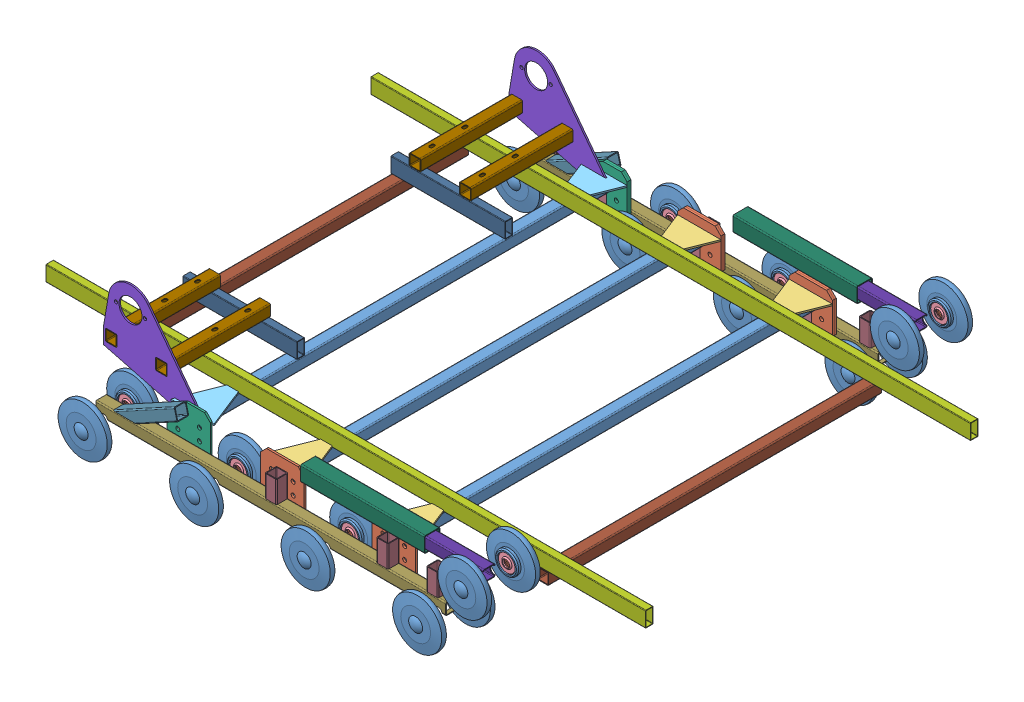
SolidWorks assembly ТП.016.001 - Рама гусеницы, configuration 00. Lengths in mm.
Overall size (1585 378.24 1275.68).
269 component instances, 35 part files, 9 mates.
Components (placement in the parent):
- ТП.016.01.01.01.00 - Рама корпуса-1: ТП.016.01.01.01.00 - Рама корпуса [00] x (-1 0 0) z (0 0 -1) size (1585 284.02 1098)
  - ТП.016.01.01.01.01.00 - Поперечная балка в сборе-1: ТП.016.01.01.01.01.00 - Поперечная балка в сборе [Центральная] at (824.8534 -30 544) size (112 110.77 1078)
    - ТП.016.01.01.01.01.01 - Поперечная балка (30х30)-1: ТП.016.01.01.01.01.01 - Поперечная балка (30х30) [--] at origin size (30 30 1068)
    - ТП.016.01.01.01.01.02 - Пластина кронштейна (5мм)-1: ТП.016.01.01.01.01.02 - Пластина кронштейна (5мм) [--] at (0 -56.7738 -5) size (112 110.77 5)
    - ТП.016.01.01.01.01.03 - Косынка верхняя (4мм)-1: ТП.016.01.01.01.01.03 - Косынка верхняя (4мм) [--] at (0 30 -10) size (112 4 104)
    - ТП.016.01.01.01.01.02 - Пластина кронштейна (5мм)-2: ТП.016.01.01.01.01.02 - Пластина кронштейна (5мм) [--] at (0 -56.7738 -1083) x (-1 0 0) z (0 0 -1) size (112 110.77 5)
    - ТП.016.01.01.01.01.03 - Косынка верхняя (4мм)-2: ТП.016.01.01.01.01.03 - Косынка верхняя (4мм) [--] at (0 30 -1078) x (-1 0 0) z (0 0 -1) size (112 4 104)
    - ТП.016.01.01.01.01.04 - Косынка нижняя (4мм)-2: ТП.016.01.01.01.01.04 - Косынка нижняя (4мм) [--] at (0 0 -1078) x (-1 0 0) z (0 0 -1) size (4 53.77 53.77)
    - ТП.016.01.01.01.01.04 - Косынка нижняя (4мм)-3: ТП.016.01.01.01.01.04 - Косынка нижняя (4мм) [--] at (0 0 -10) size (4 53.77 53.77)
    - ТП.016.01.01.01.01.05 - Пластина кронштейна задняя (5мм)-1: ТП.016.01.01.01.01.05 - Пластина кронштейна задняя (5мм) [--] at (0 -56.7738 -1083) x (-1 0 0) z (0 0 -1) size (112 110.77 5) (hidden)
    - ТП.016.01.01.01.01.06 - Косынка верхняя задняя (4мм)-1: ТП.016.01.01.01.01.06 - Косынка верхняя задняя (4мм) [--] at (-15 30 -1078) x (-1 0 0) z (0 0 -1) size (111.99 4 104) (hidden)
    - ТП.016.01.01.01.01.05 - Пластина кронштейна задняя (5мм)-2: ТП.016.01.01.01.01.05 - Пластина кронштейна задняя (5мм) [--] at (0 -56.7738 -10) x (-1 0 0) z (0 0 -1) size (112 110.77 5) (hidden)
    - ТП.016.01.01.01.01.06 - Косынка верхняя задняя (4мм)-2: ТП.016.01.01.01.01.06 - Косынка верхняя задняя (4мм) [--] at (-15 34 -10) x (-1 0 0) z (0 0 1) size (111.99 4 104) (hidden)
  - ТП.016.01.01.01.01.00 - Поперечная балка в сборе-2: ТП.016.01.01.01.01.00 - Поперечная балка в сборе [Центральная] at (536.5267 -30 544) size (112 110.77 1078)
    - ТП.016.01.01.01.01.01 - Поперечная балка (30х30)-1: ТП.016.01.01.01.01.01 - Поперечная балка (30х30) [--] at origin size (30 30 1068)
    - ТП.016.01.01.01.01.02 - Пластина кронштейна (5мм)-1: ТП.016.01.01.01.01.02 - Пластина кронштейна (5мм) [--] at (0 -56.7738 -5) size (112 110.77 5)
    - ТП.016.01.01.01.01.03 - Косынка верхняя (4мм)-1: ТП.016.01.01.01.01.03 - Косынка верхняя (4мм) [--] at (0 30 -10) size (112 4 104)
    - ТП.016.01.01.01.01.02 - Пластина кронштейна (5мм)-2: ТП.016.01.01.01.01.02 - Пластина кронштейна (5мм) [--] at (0 -56.7738 -1083) x (-1 0 0) z (0 0 -1) size (112 110.77 5)
    - ТП.016.01.01.01.01.03 - Косынка верхняя (4мм)-2: ТП.016.01.01.01.01.03 - Косынка верхняя (4мм) [--] at (0 30 -1078) x (-1 0 0) z (0 0 -1) size (112 4 104)
    - ТП.016.01.01.01.01.04 - Косынка нижняя (4мм)-2: ТП.016.01.01.01.01.04 - Косынка нижняя (4мм) [--] at (0 0 -1078) x (-1 0 0) z (0 0 -1) size (4 53.77 53.77)
    - ТП.016.01.01.01.01.04 - Косынка нижняя (4мм)-3: ТП.016.01.01.01.01.04 - Косынка нижняя (4мм) [--] at (0 0 -10) size (4 53.77 53.77)
    - ТП.016.01.01.01.01.05 - Пластина кронштейна задняя (5мм)-1: ТП.016.01.01.01.01.05 - Пластина кронштейна задняя (5мм) [--] at (0 -56.7738 -1083) x (-1 0 0) z (0 0 -1) size (112 110.77 5) (hidden)
    - ТП.016.01.01.01.01.06 - Косынка верхняя задняя (4мм)-1: ТП.016.01.01.01.01.06 - Косынка верхняя задняя (4мм) [--] at (-15 30 -1078) x (-1 0 0) z (0 0 -1) size (111.99 4 104) (hidden)
    - ТП.016.01.01.01.01.05 - Пластина кронштейна задняя (5мм)-2: ТП.016.01.01.01.01.05 - Пластина кронштейна задняя (5мм) [--] at (0 -56.7738 -10) x (-1 0 0) z (0 0 -1) size (112 110.77 5) (hidden)
    - ТП.016.01.01.01.01.06 - Косынка верхняя задняя (4мм)-2: ТП.016.01.01.01.01.06 - Косынка верхняя задняя (4мм) [--] at (-15 34 -10) x (-1 0 0) z (0 0 1) size (111.99 4 104) (hidden)
  - ТП.016.01.01.01.01.00 - Поперечная балка в сборе-3: ТП.016.01.01.01.01.00 - Поперечная балка в сборе [Задняя] at (1067.2668 -30 544) size (112 110.77 1078)
    - ТП.016.01.01.01.01.01 - Поперечная балка (30х30)-1: ТП.016.01.01.01.01.01 - Поперечная балка (30х30) [Под лебедку] at origin size (30 30 1068)
    - ТП.016.01.01.01.01.02 - Пластина кронштейна (5мм)-1: ТП.016.01.01.01.01.02 - Пластина кронштейна (5мм) [--] at (0 -56.7738 -5) size (112 110.77 5) (hidden)
    - ТП.016.01.01.01.01.03 - Косынка верхняя (4мм)-1: ТП.016.01.01.01.01.03 - Косынка верхняя (4мм) [--] at (0 30 -10) size (112 4 104) (hidden)
    - ТП.016.01.01.01.01.02 - Пластина кронштейна (5мм)-2: ТП.016.01.01.01.01.02 - Пластина кронштейна (5мм) [--] at (0 -56.7738 -1083) x (-1 0 0) z (0 0 -1) size (112 110.77 5) (hidden)
    - ТП.016.01.01.01.01.03 - Косынка верхняя (4мм)-2: ТП.016.01.01.01.01.03 - Косынка верхняя (4мм) [--] at (0 30 -1078) x (-1 0 0) z (0 0 -1) size (112 4 104) (hidden)
    - ТП.016.01.01.01.01.04 - Косынка нижняя (4мм)-2: ТП.016.01.01.01.01.04 - Косынка нижняя (4мм) [--] at (0 0 -1078) x (-1 0 0) z (0 0 -1) size (4 53.77 53.77)
    - ТП.016.01.01.01.01.04 - Косынка нижняя (4мм)-3: ТП.016.01.01.01.01.04 - Косынка нижняя (4мм) [--] at (0 0 -10) size (4 53.77 53.77)
    - ТП.016.01.01.01.01.05 - Пластина кронштейна задняя (5мм)-1: ТП.016.01.01.01.01.05 - Пластина кронштейна задняя (5мм) [--] at (0 -56.7738 -1083) x (-1 0 0) z (0 0 -1) size (112 110.77 5)
    - ТП.016.01.01.01.01.06 - Косынка верхняя задняя (4мм)-1: ТП.016.01.01.01.01.06 - Косынка верхняя задняя (4мм) [--] at (-15 30 -1078) x (-1 0 0) z (0 0 -1) size (111.99 4 104)
    - ТП.016.01.01.01.01.05 - Пластина кронштейна задняя (5мм)-2: ТП.016.01.01.01.01.05 - Пластина кронштейна задняя (5мм) [--] at (0 -56.7738 -10) x (-1 0 0) z (0 0 -1) size (112 110.77 5)
    - ТП.016.01.01.01.01.06 - Косынка верхняя задняя (4мм)-2: ТП.016.01.01.01.01.06 - Косынка верхняя задняя (4мм) [--] at (-15 34 -10) x (-1 0 0) z (0 0 1) size (111.99 4 104)
  - ТП.016.01.01.01.02 - Балка платформы боковая (40х20)-1: ТП.016.01.01.01.02 - Балка платформы боковая (40х20) [--] at (250 0 -420) x (0 0 -1) z (1 0 0) size (20 40 1550)
  - ТП.016.01.01.01.02 - Балка платформы боковая (40х20)-2: ТП.016.01.01.01.02 - Балка платформы боковая (40х20) [--] at (250 0 420) x (0 0 -1) z (1 0 0) size (20 40 1550)
  - Схема рамы ЭСКИЗ-1: Схема рамы ЭСКИЗ [--] x (0 0 -1) z (1 0 0) size (559 0 1052.27)
  - ТП.016.01.01.01.03.00 - Опора редуктора-1: ТП.016.01.01.01.03.00 - Опора редуктора [Правая] at (1235 143.2262 -526.5) x (-1 0 0) z (0 0 -1) size (276.73 227.25 267.34)
    - ТП.016.01.01.01.03.01 - Щека ведущей оси (4мм)-1: ТП.016.01.01.01.03.01 - Щека ведущей оси (4мм) [--] at origin size (249.73 227.25 4)
    - ТП.016.01.01.01.03.02 - Балка опоры ребуктора (30х30)-1: ТП.016.01.01.01.03.02 - Балка опоры ребуктора (30х30) [--] at (65 -72 0) size (30 30 267.34)
    - ТП.016.01.01.01.03.02 - Балка опоры ребуктора (30х30)-2: ТП.016.01.01.01.03.02 - Балка опоры ребуктора (30х30) [--] at (-65 -72 0) size (30 30 267.34)
    - ТП.016.01.01.01.03.02 - Балка опоры ребуктора (30х30)-3: ТП.016.01.01.01.03.02 - Балка опоры ребуктора (30х30) [--] at (95 -72 -4) x (-1 0 0) z (0 0 -1) size (30 30 267.34) (hidden)
    - ТП.016.01.01.01.03.02 - Балка опоры ребуктора (30х30)-4: ТП.016.01.01.01.03.02 - Балка опоры ребуктора (30х30) [--] at (-35 -72 -4) x (-1 0 0) z (0 0 -1) size (30 30 267.34) (hidden)
    - ТП.016.01.01.01.03.03 - Пол под редуктор (3мм)-1: ТП.016.01.01.01.03.03 - Пол под редуктор (3мм) [--] at (65 -143.2262 -181.9182) x (0 0 -1) z (1 0 0) size (130.84 76.23 264.73)
  - ТП.016.01.01.01.03.00 - Опора редуктора-2: ТП.016.01.01.01.03.00 - Опора редуктора [Левая] at (1235 143.2262 522.5) x (-1 0 0) z (0 0 -1) size (276.73 227.25 267.34)
    - ТП.016.01.01.01.03.01 - Щека ведущей оси (4мм)-1: ТП.016.01.01.01.03.01 - Щека ведущей оси (4мм) [--] at origin size (249.73 227.25 4)
    - ТП.016.01.01.01.03.02 - Балка опоры ребуктора (30х30)-1: ТП.016.01.01.01.03.02 - Балка опоры ребуктора (30х30) [--] at (65 -72 0) size (30 30 267.34) (hidden)
    - ТП.016.01.01.01.03.02 - Балка опоры ребуктора (30х30)-2: ТП.016.01.01.01.03.02 - Балка опоры ребуктора (30х30) [--] at (-65 -72 0) size (30 30 267.34) (hidden)
    - ТП.016.01.01.01.03.02 - Балка опоры ребуктора (30х30)-3: ТП.016.01.01.01.03.02 - Балка опоры ребуктора (30х30) [--] at (95 -72 -4) x (-1 0 0) z (0 0 -1) size (30 30 267.34)
    - ТП.016.01.01.01.03.02 - Балка опоры ребуктора (30х30)-4: ТП.016.01.01.01.03.02 - Балка опоры ребуктора (30х30) [--] at (-35 -72 -4) x (-1 0 0) z (0 0 -1) size (30 30 267.34)
    - ТП.016.01.01.01.03.03 - Пол под редуктор (3мм)-1: ТП.016.01.01.01.03.03 - Пол под редуктор (3мм) [--] at (65 -143.2262 177.9182) x (0 0 -1) z (1 0 0) size (130.84 76.23 264.73)
  - ТП.016.01.01.01.04 - Опора короткая под редуктор (40х20)-1: ТП.016.01.01.01.04 - Опора короткая под редуктор (40х20) [--] at (1052.2668 0 -259.1637) x (0 0 -1) z (1 0 0) size (20 40 294.73)
  - ТП.016.01.01.01.04 - Опора короткая под редуктор (40х20)-2: ТП.016.01.01.01.04 - Опора короткая под редуктор (40х20) [--] at (1052.2668 0 279.1637) x (0 0 -1) z (1 0 0) size (20 40 294.73)
  - ТП.016.01.01.01.05 - Поперечина короткая (30х30)-1: ТП.016.01.01.01.05 - Поперечина короткая (30х30) [--] at (1347 0 0) size (30 30 860)
  - ТП.016.01.01.01.05 - Поперечина короткая (30х30)-2: ТП.016.01.01.01.05 - Поперечина короткая (30х30) [--] at (280 0 0) size (30 30 860)
  - ТП.016.01.01.01.06 - Поддержка центральная (40х20)-1: ТП.016.01.01.01.06 - Поддержка центральная (40х20) [--] at (45 -9.1741 -23) x (0 0 1) z (-1 0 0) size (20 40 596.53)
  - ТП.016.01.01.01.06 - Поддержка центральная (40х20)-2: ТП.016.01.01.01.06 - Поддержка центральная (40х20) [--] at (45 -9.1741 43) x (0 0 1) z (-1 0 0) size (20 40 596.53)
  - ТП.016.01.01.01.07 - Пол перед (3мм)-1: ТП.016.01.01.01.07 - Пол перед (3мм) [Правый] at (0 0 -410) x (0 0 -1) z (1 0 0) size (377 29.49 517.11)
  - ТП.016.01.01.01.07 - Пол перед (3мм)-2: ТП.016.01.01.01.07 - Пол перед (3мм) [Левый] at (0 0 -344) x (0 0 -1) z (1 0 0) size (754 29.49 517.11)
  - ТП.016.01.01.01.08 - Пол центр (2мм)-1: ТП.016.01.01.01.08 - Пол центр (2мм) [--] at (250 0 0) x (0 0 -1) z (1 0 0) size (820 12 817.27)
  - ТП.016.01.01.01.09 - Задний бампер (40х20)-1: ТП.016.01.01.01.09 - Задний бампер (40х20) [--] at (1570 0 0) size (20 40 860)
  - ТП.016.01.01.01.10 - Пол капота (3мм)-1: ТП.016.01.01.01.10 - Пол капота (3мм) [--] at (1550 0 0) x (0 0 1) z (-1 0 0) size (820 13 482.73)
  - Гайка (ГОСТ ISO 4032-2014)-1: Гайка (ГОСТ ISO 4032-2014) [Гайка М6 (ГОСТ ISO 4032)] at (153.1386 -2.6 64.0253) x (-0.998033 0 -0.062689) z (0 1 0) size (10 11.05 5.2)
  - Гайка (ГОСТ ISO 4032-2014)-2: Гайка (ГОСТ ISO 4032-2014) [Гайка М6 (ГОСТ ISO 4032)] at (403.0634 -2.6 70.156) x (-0.991964 0 0.126519) z (0 1 0) size (10 11.05 5.2)
  - Гайка (ГОСТ ISO 4032-2014)-3: Гайка (ГОСТ ISO 4032-2014) [Гайка М6 (ГОСТ ISO 4032)] at (672.9822 -2.6 76.7772) x (-0.941367 0 0.337385) z (0 1 0) size (10 11.05 5.2)
  - Гайка (ГОСТ ISO 4032-2014)-4: Гайка (ГОСТ ISO 4032-2014) [Гайка М6 (ГОСТ ISO 4032)] at (1021.6211 -2.6 85.3294) x (-0.83604 0 0.548669) z (0 1 0) size (10 11.05 5.2)
  - Гайка (ГОСТ ISO 4032-2014)-5: Гайка (ГОСТ ISO 4032-2014) [Гайка М6 (ГОСТ ISO 4032)] at (1021.6211 -2.6 -85.3294) x (-0.680834 0 0.732437) z (0 1 0) size (10 11.05 5.2)
  - Гайка (ГОСТ ISO 4032-2014)-6: Гайка (ГОСТ ISO 4032-2014) [Гайка М6 (ГОСТ ISO 4032)] at (672.9822 -2.6 -76.7772) x (-0.498939 0 0.866637) z (0 1 0) size (10 11.05 5.2)
  - Гайка (ГОСТ ISO 4032-2014)-7: Гайка (ГОСТ ISO 4032-2014) [Гайка М6 (ГОСТ ISO 4032)] at (403.0634 -2.6 -70.156) x (-0.323185 0 0.946336) z (0 1 0) size (10 11.05 5.2)
  - Гайка (ГОСТ ISO 4032-2014)-8: Гайка (ГОСТ ISO 4032-2014) [Гайка М6 (ГОСТ ISO 4032)] at (153.1386 -2.6 -64.0253) x (-0.182176 0 0.983266) z (0 1 0) size (10 11.05 5.2)
- ТП.016.02.00 - Гусеничный модуль в сборе-1: ТП.016.02.00 - Гусеничный модуль в сборе [Левый] at (-392.3634 -86.7738 -559) x (-1 0 0) z (0 0 -1) size (1147.02 302.71 157.68)
  - ТП.016.02.01.00 - Модуль гусеницы силовой-1: ТП.016.02.01.00 - Модуль гусеницы силовой [Левый] at origin size (904.98 176.07 133.68)
    - ТП.016.02.01.01.00 - Рама гусеницы с осями-1: ТП.016.02.01.01.00 - Рама гусеницы с осями [00] at origin size (904.98 176.07 133.68)
      - ТП.016.02.01.01.01 - Нижняя балка гуленицы (30х30)-1: ТП.016.02.01.01.01 - Нижняя балка гуленицы (30х30) [--] at origin size (904.98 30 30)
      - ТП.016.02.01.01.02(02) - Ось цельная 21_3мм-1: ТП.016.02.01.01.02(02) - Ось цельная 21_3мм [--] x (0 0 1) z (-1 0 0) size (133.68 21.3 21.3)
      - ТП.016.02.01.01.02(02) - Ось цельная 21_3мм-2: ТП.016.02.01.01.02(02) - Ось цельная 21_3мм [--] at (288.3267 0 0) x (0 0 1) z (-0.987351 0.158553 0) size (133.68 21.3 21.3)
      - ТП.016.02.01.01.02(02) - Ось цельная 21_3мм-3: ТП.016.02.01.01.02(02) - Ось цельная 21_3мм [--] at (576.6534 0 0) x (0 0 1) z (-0.959125 0.282984 0) size (133.68 21.3 21.3)
      - ТП.016.02.01.01.02(02) - Ось цельная 21_3мм-4: ТП.016.02.01.01.02(02) - Ось цельная 21_3мм [--] at (864.9801 0 0) x (0 0 1) z (-0.928571 0.371154 0) size (133.68 21.3 21.3)
      - ТП.016.02.01.01.03 - Связка балок гусеничного модуля-1: ТП.016.02.01.01.03 - Связка балок гусеничного модуля [--] at (0 86.7738 0) x (-1 0 0) z (0 0 -1) size (30 56.77 30)
      - ТП.016.02.01.01.03 - Связка балок гусеничного модуля-2: ТП.016.02.01.01.03 - Связка балок гусеничного модуля [--] at (129.1634 86.7738 0) x (-1 0 0) z (0 0 -1) size (30 56.77 30)
      - ТП.016.02.01.01.03 - Связка балок гусеничного модуля-3: ТП.016.02.01.01.03 - Связка балок гусеничного модуля [--] at (417.4901 86.7738 0) x (-1 0 0) z (0 0 -1) size (30 56.77 30)
      - ТП.016.02.01.01.04 - Верхняя балка рамы гусеницы-1: ТП.016.02.01.01.04 - Верхняя балка рамы гусеницы [--] at (0 136.7738 0) x (0 0 1) z (-1 0 0) size (30 129.94 872.16)
      - ТП.016.02.01.01.05 - Задняя косая-1: ТП.016.02.01.01.05 - Задняя косая [--] at (864.9801 0 -15) x (0 0 -1) z (0.877984 -0.478691 0) size (30 30 181.27)
      - ТП.016.02.01.01.06.00 - Стакан натяжителя-1: ТП.016.02.01.01.06.00 - Стакан натяжителя [00] at (30 136.7738 0) x (-1 0 0) z (0 0 -1) size (320 50.91 50.91)
        - ТП.016.02.01.01.06.01 - Рубашка штока ролика натяжного-1: ТП.016.02.01.01.06.01 - Рубашка штока ролика натяжного [--] at origin size (320 40 40)
        - ТП.016.02.01.01.06.02 - Гайка рубашки штока-1: ТП.016.02.01.01.06.02 - Гайка рубашки штока [--] at (-320 0 0) x (0 -0.713098 -0.701064) z (1 0 0) size (36 36 20)
    - ТП.016.01.01.01.01.02 - Пластина кронштейна (5мм)-1: ТП.016.01.01.01.01.02 - Пластина кронштейна (5мм) [--] at (144.1634 0 20) size (112 110.77 5) (hidden)
    - ТП.016.01.01.01.01.02 - Пластина кронштейна (5мм)-2: ТП.016.01.01.01.01.02 - Пластина кронштейна (5мм) [--] at (432.4901 0 20) size (112 110.77 5) (hidden)
    - ТП.016.01.01.01.01.05 - Пластина кронштейна задняя (5мм)-1: ТП.016.01.01.01.01.05 - Пластина кронштейна задняя (5мм) [--] at (674.9034 0 15) x (-1 0 0) z (0 0 -1) size (112 110.77 5) (hidden)
    - ТП.016.01.01.01.01.02 - Пластина кронштейна (5мм)-4: ТП.016.01.01.01.01.02 - Пластина кронштейна (5мм) [--] at (144.1634 0 -20) x (-1 0 0) z (0 0 -1) size (112 110.77 5)
    - ТП.016.01.01.01.01.02 - Пластина кронштейна (5мм)-6: ТП.016.01.01.01.01.02 - Пластина кронштейна (5мм) [--] at (432.4901 0 -20) x (-1 0 0) z (0 0 -1) size (112 110.77 5)
    - ТП.016.01.01.01.01.05 - Пластина кронштейна задняя (5мм)-2: ТП.016.01.01.01.01.05 - Пластина кронштейна задняя (5мм) [--] at (674.9034 0 -20) x (-1 0 0) z (0 0 -1) size (112 110.77 5)
  - ТП.016.02.02.00 - Натяжитель гусеницы-1: ТП.016.02.02.00 - Натяжитель гусеницы [00] at (-117 136.7738 0) x (-1 0 0) z (0 0 1) size (371.74 149.44 157.68)
    - ТП.016.02.02.01.00 - Толкатель натяжки-1: ТП.016.02.02.01.00 - Толкатель натяжки [00] at origin size (311.12 30 133.68)
      - ТП.016.02.02.01.01 - Шток натяжного ролика (30х30)-1: ТП.016.02.02.01.01 - Шток натяжного ролика (30х30) [--] at origin size (297.02 30 30)
      - ТП.016.02.01.01.02(02) - Ось цельная 21_3мм-1: ТП.016.02.01.01.02(02) - Ось цельная 21_3мм [--] x (0 0 1) z (-0.910058 0.41448 0) size (133.68 21.3 21.3)
      - ТП.016.02.02.01.02 - Заглушка штока-1: ТП.016.02.02.01.02 - Заглушка штока [--] at (-297.0168 0 0) x (0 -1 0) z (1 0 0) size (26 26 20)
    - Каток 129(47) в сборе-1: Каток 129(47) в сборе [00] at (0 0 62.8416) x (0 0 1) z (1 0 0) size (35.7 129 129)
      - Каток 129(47)-1: Каток 129(47) [--] at origin size (35 129 129)
      - Подшипник ГОСТ 8338-75 -1: Подшипник ГОСТ 8338-75  [Подшипник 204 ГОСТ 8338-75] at (-1 0 0) x (1 0 0) z (0 -0.327433 -0.944874) size (14 47 47)
      - Стопор внутренний до 165мм (ГОСТ 13943-86)-1: Стопор внутренний до 165мм (ГОСТ 13943-86) [Кольцо 47] at (-8 0 0) x (0 0.910839 0.412761) z (-1 0 0) size (49.5 51.2 1.7)
      - Сальник 47х20-1: Сальник 47х20 [--] at (-9.7 0 0) x (-1 0 0) z (0 0.937697 -0.347453) size (10 47 47)
    - Каток 129(47) в сборе-2: Каток 129(47) в сборе [00] at (0 0 -62.8416) x (0 0 -1) z (-0.173648 0.984808 0) size (35.7 129 129)
      - Каток 129(47)-1: Каток 129(47) [--] at origin size (35 129 129)
      - Подшипник ГОСТ 8338-75 -1: Подшипник ГОСТ 8338-75  [Подшипник 204 ГОСТ 8338-75] at (-1 0 0) x (1 0 0) z (0 -0.327433 -0.944874) size (14 47 47)
      - Стопор внутренний до 165мм (ГОСТ 13943-86)-1: Стопор внутренний до 165мм (ГОСТ 13943-86) [Кольцо 47] at (-8 0 0) x (0 0.910839 0.412761) z (-1 0 0) size (49.5 51.2 1.7)
      - Сальник 47х20-1: Сальник 47х20 [--] at (-9.7 0 0) x (-1 0 0) z (0 0.937697 -0.347453) size (10 47 47)
    - ТП.016.02.02.02 - Шайба оси-1: ТП.016.02.02.02 - Шайба оси [--] at (0 0 -66.3614) x (0 0 1) z (0.48394 0.875101 0) size (4 24 24)
    - Болты с шестигранной головкой кт.В (ГОСТ 7798-70)-1: Болты с шестигранной головкой кт.В (ГОСТ 7798-70) [Болт М6-6gx14(S10) ГОСТ 7798-77] at (0 0 -69.3416) x (0 0 1) z (0.143998 -0.989578 0) size (18 10.9 10)
    - ТП.016.02.02.02 - Шайба оси-2: ТП.016.02.02.02 - Шайба оси [--] at (0 0 66.3614) x (0 0 -1) z (0.777771 0.628548 0) size (4 24 24)
    - Болты с шестигранной головкой кт.В (ГОСТ 7798-70)-2: Болты с шестигранной головкой кт.В (ГОСТ 7798-70) [Болт М6-6gx14(S10) ГОСТ 7798-77] at (0 0 69.3416) x (0 0 -1) z (-0.999549 -0.030028 0) size (18 10.9 10)
  - ТП.016.02.03 - Винт натяжителя-1: ТП.016.02.03 - Винт натяжителя [--] at (350.0168 136.7738 0) x (0 -0.01927 -0.999814) z (-1 0 0) size (20 20 231.35)
  - Каток 129(47) в сборе-1: Каток 129(47) в сборе [00] at (0 0 -62.8416) x (0 0 -1) z (-0.261474 0.96521 0) size (35.7 129 129)
    - Каток 129(47)-1: Каток 129(47) [--] at origin size (35 129 129)
    - Подшипник ГОСТ 8338-75 -1: Подшипник ГОСТ 8338-75  [Подшипник 204 ГОСТ 8338-75] at (-1 0 0) x (1 0 0) z (0 -0.327433 -0.944874) size (14 47 47)
    - Стопор внутренний до 165мм (ГОСТ 13943-86)-1: Стопор внутренний до 165мм (ГОСТ 13943-86) [Кольцо 47] at (-8 0 0) x (0 0.910839 0.412761) z (-1 0 0) size (49.5 51.2 1.7)
    - Сальник 47х20-1: Сальник 47х20 [--] at (-9.7 0 0) x (-1 0 0) z (0 0.937697 -0.347453) size (10 47 47)
  - Каток 129(47) в сборе-2: Каток 129(47) в сборе [00] at (288.3267 0 -62.8416) x (0 0 -1) z (-0.411203 0.911544 0) size (35.7 129 129)
    - Каток 129(47)-1: Каток 129(47) [--] at origin size (35 129 129)
    - Подшипник ГОСТ 8338-75 -1: Подшипник ГОСТ 8338-75  [Подшипник 204 ГОСТ 8338-75] at (-1 0 0) x (1 0 0) z (0 -0.327433 -0.944874) size (14 47 47)
    - Стопор внутренний до 165мм (ГОСТ 13943-86)-1: Стопор внутренний до 165мм (ГОСТ 13943-86) [Кольцо 47] at (-8 0 0) x (0 0.910839 0.412761) z (-1 0 0) size (49.5 51.2 1.7)
    - Сальник 47х20-1: Сальник 47х20 [--] at (-9.7 0 0) x (-1 0 0) z (0 0.937697 -0.347453) size (10 47 47)
  - Каток 129(47) в сборе-4: Каток 129(47) в сборе [00] at (576.6534 0 -62.8416) x (0 0 -1) z (-0.523925 0.851764 0) size (35.7 129 129)
    - Каток 129(47)-1: Каток 129(47) [--] at origin size (35 129 129)
    - Подшипник ГОСТ 8338-75 -1: Подшипник ГОСТ 8338-75  [Подшипник 204 ГОСТ 8338-75] at (-1 0 0) x (1 0 0) z (0 -0.327433 -0.944874) size (14 47 47)
    - Стопор внутренний до 165мм (ГОСТ 13943-86)-1: Стопор внутренний до 165мм (ГОСТ 13943-86) [Кольцо 47] at (-8 0 0) x (0 0.910839 0.412761) z (-1 0 0) size (49.5 51.2 1.7)
    - Сальник 47х20-1: Сальник 47х20 [--] at (-9.7 0 0) x (-1 0 0) z (0 0.937697 -0.347453) size (10 47 47)
  - Каток 129(47) в сборе-6: Каток 129(47) в сборе [00] at (864.9801 0 -62.8416) x (0 0 -1) z (0.601039 -0.79922 0) size (35.7 129 129)
    - Каток 129(47)-1: Каток 129(47) [--] at origin size (35 129 129)
    - Подшипник ГОСТ 8338-75 -1: Подшипник ГОСТ 8338-75  [Подшипник 204 ГОСТ 8338-75] at (-1 0 0) x (1 0 0) z (0 -0.327433 -0.944874) size (14 47 47)
    - Стопор внутренний до 165мм (ГОСТ 13943-86)-1: Стопор внутренний до 165мм (ГОСТ 13943-86) [Кольцо 47] at (-8 0 0) x (0 0.910839 0.412761) z (-1 0 0) size (49.5 51.2 1.7)
    - Сальник 47х20-1: Сальник 47х20 [--] at (-9.7 0 0) x (-1 0 0) z (0 0.937697 -0.347453) size (10 47 47)
  - Каток 129(47) в сборе-8: Каток 129(47) в сборе [00] at (864.9801 0 62.8416) x (0 0 1) z (0.907466 0.420125 0) size (35.7 129 129)
    - Каток 129(47)-1: Каток 129(47) [--] at origin size (35 129 129)
    - Подшипник ГОСТ 8338-75 -1: Подшипник ГОСТ 8338-75  [Подшипник 204 ГОСТ 8338-75] at (-1 0 0) x (1 0 0) z (0 -0.327433 -0.944874) size (14 47 47)
    - Стопор внутренний до 165мм (ГОСТ 13943-86)-1: Стопор внутренний до 165мм (ГОСТ 13943-86) [Кольцо 47] at (-8 0 0) x (0 0.910839 0.412761) z (-1 0 0) size (49.5 51.2 1.7)
    - Сальник 47х20-1: Сальник 47х20 [--] at (-9.7 0 0) x (-1 0 0) z (0 0.937697 -0.347453) size (10 47 47)
  - Каток 129(47) в сборе-10: Каток 129(47) в сборе [00] at (576.6534 0 62.8416) x (0 0 1) z (0.820726 0.571322 0) size (35.7 129 129)
    - Каток 129(47)-1: Каток 129(47) [--] at origin size (35 129 129)
    - Подшипник ГОСТ 8338-75 -1: Подшипник ГОСТ 8338-75  [Подшипник 204 ГОСТ 8338-75] at (-1 0 0) x (1 0 0) z (0 -0.327433 -0.944874) size (14 47 47)
    - Стопор внутренний до 165мм (ГОСТ 13943-86)-1: Стопор внутренний до 165мм (ГОСТ 13943-86) [Кольцо 47] at (-8 0 0) x (0 0.910839 0.412761) z (-1 0 0) size (49.5 51.2 1.7)
    - Сальник 47х20-1: Сальник 47х20 [--] at (-9.7 0 0) x (-1 0 0) z (0 0.937697 -0.347453) size (10 47 47)
  - Каток 129(47) в сборе-12: Каток 129(47) в сборе [00] at (288.3267 0 62.8416) x (0 0 1) z (0.709048 0.70516 0) size (35.7 129 129)
    - Каток 129(47)-1: Каток 129(47) [--] at origin size (35 129 129)
    - Подшипник ГОСТ 8338-75 -1: Подшипник ГОСТ 8338-75  [Подшипник 204 ГОСТ 8338-75] at (-1 0 0) x (1 0 0) z (0 -0.327433 -0.944874) size (14 47 47)
    - Стопор внутренний до 165мм (ГОСТ 13943-86)-1: Стопор внутренний до 165мм (ГОСТ 13943-86) [Кольцо 47] at (-8 0 0) x (0 0.910839 0.412761) z (-1 0 0) size (49.5 51.2 1.7)
    - Сальник 47х20-1: Сальник 47х20 [--] at (-9.7 0 0) x (-1 0 0) z (0 0.937697 -0.347453) size (10 47 47)
  - Каток 129(47) в сборе-14: Каток 129(47) в сборе [00] at (0 0 62.8416) x (0 0 1) z (0.575827 0.817572 0) size (35.7 129 129)
    - Каток 129(47)-1: Каток 129(47) [--] at origin size (35 129 129)
    - Подшипник ГОСТ 8338-75 -1: Подшипник ГОСТ 8338-75  [Подшипник 204 ГОСТ 8338-75] at (-1 0 0) x (1 0 0) z (0 -0.327433 -0.944874) size (14 47 47)
    - Стопор внутренний до 165мм (ГОСТ 13943-86)-1: Стопор внутренний до 165мм (ГОСТ 13943-86) [Кольцо 47] at (-8 0 0) x (0 0.910839 0.412761) z (-1 0 0) size (49.5 51.2 1.7)
    - Сальник 47х20-1: Сальник 47х20 [--] at (-9.7 0 0) x (-1 0 0) z (0 0.937697 -0.347453) size (10 47 47)
  - ТП.016.02.02.02 - Шайба оси-1: ТП.016.02.02.02 - Шайба оси [--] at (0 0 -66.3614) x (0 0 1) z (0.502694 0.864464 0) size (4 24 24)
  - Болты с шестигранной головкой кт.В (ГОСТ 7798-70)-1: Болты с шестигранной головкой кт.В (ГОСТ 7798-70) [Болт М6-6gx16(S10) ГОСТ 7798-77] at (0 0 -69.3416) x (0 0 1) z (0.899536 0.436848 0) size (20 10.9 10)
  - ТП.016.02.02.02 - Шайба оси-2: ТП.016.02.02.02 - Шайба оси [--] at (288.3267 0 -66.3614) x (0 0 1) z (0.359272 0.933233 0) size (4 24 24)
  - Болты с шестигранной головкой кт.В (ГОСТ 7798-70)-2: Болты с шестигранной головкой кт.В (ГОСТ 7798-70) [Болт М6-6gx16(S10) ГОСТ 7798-77] at (288.3267 0 -69.3416) x (0 0 1) z (0.818894 0.573945 0) size (20 10.9 10)
  - ТП.016.02.02.02 - Шайба оси-4: ТП.016.02.02.02 - Шайба оси [--] at (576.6534 0 -66.3614) x (0 0 1) z (0.237517 0.971383 0) size (4 24 24)
  - Болты с шестигранной головкой кт.В (ГОСТ 7798-70)-4: Болты с шестигранной головкой кт.В (ГОСТ 7798-70) [Болт М6-6gx16(S10) ГОСТ 7798-77] at (576.6534 0 -69.3416) x (0 0 1) z (0.739146 0.673545 0) size (20 10.9 10)
  - ТП.016.02.02.02 - Шайба оси-6: ТП.016.02.02.02 - Шайба оси [--] at (864.9801 0 -66.3614) x (0 0 1) z (0.145939 0.989294 0) size (4 24 24)
  - Болты с шестигранной головкой кт.В (ГОСТ 7798-70)-6: Болты с шестигранной головкой кт.В (ГОСТ 7798-70) [Болт М6-6gx16(S10) ГОСТ 7798-77] at (864.9801 0 -69.3416) x (0 0 1) z (0.673145 0.73951 0) size (20 10.9 10)
  - ТП.016.02.02.02 - Шайба оси-8: ТП.016.02.02.02 - Шайба оси [--] at (864.9801 0 66.3614) x (0 0 -1) z (0.339092 0.940753 0) size (4 24 24)
  - Болты с шестигранной головкой кт.В (ГОСТ 7798-70)-8: Болты с шестигранной головкой кт.В (ГОСТ 7798-70) [Болт М6-6gx16(S10) ГОСТ 7798-77] at (864.9801 0 69.3416) x (0 0 -1) z (-0.243566 0.969884 0) size (20 10.9 10)
  - ТП.016.02.02.02 - Шайба оси-11: ТП.016.02.02.02 - Шайба оси [--] at (576.6534 0 66.3614) x (0 0 -1) z (0.170581 0.985344 0) size (4 24 24)
  - Болты с шестигранной головкой кт.В (ГОСТ 7798-70)-11: Болты с шестигранной головкой кт.В (ГОСТ 7798-70) [Болт М6-6gx16(S10) ГОСТ 7798-77] at (576.6534 0 69.3416) x (0 0 -1) z (-0.408284 0.912855 0) size (20 10.9 10)
  - ТП.016.02.02.02 - Шайба оси-13: ТП.016.02.02.02 - Шайба оси [--] at (288.3267 0 66.3614) x (0 0 -1) z (-0.003114 0.999995 0) size (4 24 24)
  - Болты с шестигранной головкой кт.В (ГОСТ 7798-70)-13: Болты с шестигранной головкой кт.В (ГОСТ 7798-70) [Болт М6-6gx16(S10) ГОСТ 7798-77] at (288.3267 0 69.3416) x (0 0 -1) z (-0.560597 0.828089 0) size (20 10.9 10)
  - ТП.016.02.02.02 - Шайба оси-15: ТП.016.02.02.02 - Шайба оси [--] at (0 0 66.3614) x (0 0 -1) z (-0.176714 0.984262 0) size (4 24 24)
  - Болты с шестигранной головкой кт.В (ГОСТ 7798-70)-15: Болты с шестигранной головкой кт.В (ГОСТ 7798-70) [Болт М6-6gx16(S10) ГОСТ 7798-77] at (0 0 69.3416) x (0 0 -1) z (-0.695876 0.718162 0) size (20 10.9 10)
- ТП.016.02.00 - Гусеничный модуль в сборе-2: ТП.016.02.00 - Гусеничный модуль в сборе [Правый] at (-392.3634 -86.7738 559) x (-1 0 0) z (0 0 -1) size (1147.02 302.71 157.68)
  - ТП.016.02.01.00 - Модуль гусеницы силовой-1: ТП.016.02.01.00 - Модуль гусеницы силовой [Правый] at origin size (904.98 176.07 133.68)
    - ТП.016.02.01.01.00 - Рама гусеницы с осями-1: ТП.016.02.01.01.00 - Рама гусеницы с осями [00] at origin size (904.98 176.07 133.68)
      - ТП.016.02.01.01.01 - Нижняя балка гуленицы (30х30)-1: ТП.016.02.01.01.01 - Нижняя балка гуленицы (30х30) [--] at origin size (904.98 30 30)
      - ТП.016.02.01.01.02(02) - Ось цельная 21_3мм-1: ТП.016.02.01.01.02(02) - Ось цельная 21_3мм [--] x (0 0 1) z (-1 0 0) size (133.68 21.3 21.3)
      - ТП.016.02.01.01.02(02) - Ось цельная 21_3мм-2: ТП.016.02.01.01.02(02) - Ось цельная 21_3мм [--] at (288.3267 0 0) x (0 0 1) z (-0.987351 0.158553 0) size (133.68 21.3 21.3)
      - ТП.016.02.01.01.02(02) - Ось цельная 21_3мм-3: ТП.016.02.01.01.02(02) - Ось цельная 21_3мм [--] at (576.6534 0 0) x (0 0 1) z (-0.959125 0.282984 0) size (133.68 21.3 21.3)
      - ТП.016.02.01.01.02(02) - Ось цельная 21_3мм-4: ТП.016.02.01.01.02(02) - Ось цельная 21_3мм [--] at (864.9801 0 0) x (0 0 1) z (-0.928571 0.371154 0) size (133.68 21.3 21.3)
      - ТП.016.02.01.01.03 - Связка балок гусеничного модуля-1: ТП.016.02.01.01.03 - Связка балок гусеничного модуля [--] at (0 86.7738 0) x (-1 0 0) z (0 0 -1) size (30 56.77 30)
      - ТП.016.02.01.01.03 - Связка балок гусеничного модуля-2: ТП.016.02.01.01.03 - Связка балок гусеничного модуля [--] at (129.1634 86.7738 0) x (-1 0 0) z (0 0 -1) size (30 56.77 30)
      - ТП.016.02.01.01.03 - Связка балок гусеничного модуля-3: ТП.016.02.01.01.03 - Связка балок гусеничного модуля [--] at (417.4901 86.7738 0) x (-1 0 0) z (0 0 -1) size (30 56.77 30)
      - ТП.016.02.01.01.04 - Верхняя балка рамы гусеницы-1: ТП.016.02.01.01.04 - Верхняя балка рамы гусеницы [--] at (0 136.7738 0) x (0 0 1) z (-1 0 0) size (30 129.94 872.16)
      - ТП.016.02.01.01.05 - Задняя косая-1: ТП.016.02.01.01.05 - Задняя косая [--] at (864.9801 0 -15) x (0 0 -1) z (0.877984 -0.478691 0) size (30 30 181.27)
      - ТП.016.02.01.01.06.00 - Стакан натяжителя-1: ТП.016.02.01.01.06.00 - Стакан натяжителя [00] at (30 136.7738 0) x (-1 0 0) z (0 0 -1) size (320 50.91 50.91)
        - ТП.016.02.01.01.06.01 - Рубашка штока ролика натяжного-1: ТП.016.02.01.01.06.01 - Рубашка штока ролика натяжного [--] at origin size (320 40 40)
        - ТП.016.02.01.01.06.02 - Гайка рубашки штока-1: ТП.016.02.01.01.06.02 - Гайка рубашки штока [--] at (-320 0 0) x (0 -0.713098 -0.701064) z (1 0 0) size (36 36 20)
    - ТП.016.01.01.01.01.02 - Пластина кронштейна (5мм)-1: ТП.016.01.01.01.01.02 - Пластина кронштейна (5мм) [--] at (144.1634 0 20) size (112 110.77 5)
    - ТП.016.01.01.01.01.02 - Пластина кронштейна (5мм)-2: ТП.016.01.01.01.01.02 - Пластина кронштейна (5мм) [--] at (432.4901 0 20) size (112 110.77 5)
    - ТП.016.01.01.01.01.05 - Пластина кронштейна задняя (5мм)-1: ТП.016.01.01.01.01.05 - Пластина кронштейна задняя (5мм) [--] at (674.9034 0 15) x (-1 0 0) z (0 0 -1) size (112 110.77 5)
    - ТП.016.01.01.01.01.02 - Пластина кронштейна (5мм)-4: ТП.016.01.01.01.01.02 - Пластина кронштейна (5мм) [--] at (144.1634 0 -20) x (-1 0 0) z (0 0 -1) size (112 110.77 5) (hidden)
    - ТП.016.01.01.01.01.02 - Пластина кронштейна (5мм)-6: ТП.016.01.01.01.01.02 - Пластина кронштейна (5мм) [--] at (432.4901 0 -20) x (-1 0 0) z (0 0 -1) size (112 110.77 5) (hidden)
    - ТП.016.01.01.01.01.05 - Пластина кронштейна задняя (5мм)-2: ТП.016.01.01.01.01.05 - Пластина кронштейна задняя (5мм) [--] at (674.9034 0 -20) x (-1 0 0) z (0 0 -1) size (112 110.77 5) (hidden)
  - ТП.016.02.02.00 - Натяжитель гусеницы-1: ТП.016.02.02.00 - Натяжитель гусеницы [00] at (-117 136.7738 0) x (-1 0 0) z (0 0 1) size (371.74 149.44 157.68)
    - ТП.016.02.02.01.00 - Толкатель натяжки-1: ТП.016.02.02.01.00 - Толкатель натяжки [00] at origin size (311.12 30 133.68)
      - ТП.016.02.02.01.01 - Шток натяжного ролика (30х30)-1: ТП.016.02.02.01.01 - Шток натяжного ролика (30х30) [--] at origin size (297.02 30 30)
      - ТП.016.02.01.01.02(02) - Ось цельная 21_3мм-1: ТП.016.02.01.01.02(02) - Ось цельная 21_3мм [--] x (0 0 1) z (-0.910058 0.41448 0) size (133.68 21.3 21.3)
      - ТП.016.02.02.01.02 - Заглушка штока-1: ТП.016.02.02.01.02 - Заглушка штока [--] at (-297.0168 0 0) x (0 -1 0) z (1 0 0) size (26 26 20)
    - Каток 129(47) в сборе-1: Каток 129(47) в сборе [00] at (0 0 62.8416) x (0 0 1) z (1 0 0) size (35.7 129 129)
      - Каток 129(47)-1: Каток 129(47) [--] at origin size (35 129 129)
      - Подшипник ГОСТ 8338-75 -1: Подшипник ГОСТ 8338-75  [Подшипник 204 ГОСТ 8338-75] at (-1 0 0) x (1 0 0) z (0 -0.327433 -0.944874) size (14 47 47)
      - Стопор внутренний до 165мм (ГОСТ 13943-86)-1: Стопор внутренний до 165мм (ГОСТ 13943-86) [Кольцо 47] at (-8 0 0) x (0 0.910839 0.412761) z (-1 0 0) size (49.5 51.2 1.7)
      - Сальник 47х20-1: Сальник 47х20 [--] at (-9.7 0 0) x (-1 0 0) z (0 0.937697 -0.347453) size (10 47 47)
    - Каток 129(47) в сборе-2: Каток 129(47) в сборе [00] at (0 0 -62.8416) x (0 0 -1) z (-0.173648 0.984808 0) size (35.7 129 129)
      - Каток 129(47)-1: Каток 129(47) [--] at origin size (35 129 129)
      - Подшипник ГОСТ 8338-75 -1: Подшипник ГОСТ 8338-75  [Подшипник 204 ГОСТ 8338-75] at (-1 0 0) x (1 0 0) z (0 -0.327433 -0.944874) size (14 47 47)
      - Стопор внутренний до 165мм (ГОСТ 13943-86)-1: Стопор внутренний до 165мм (ГОСТ 13943-86) [Кольцо 47] at (-8 0 0) x (0 0.910839 0.412761) z (-1 0 0) size (49.5 51.2 1.7)
      - Сальник 47х20-1: Сальник 47х20 [--] at (-9.7 0 0) x (-1 0 0) z (0 0.937697 -0.347453) size (10 47 47)
    - ТП.016.02.02.02 - Шайба оси-1: ТП.016.02.02.02 - Шайба оси [--] at (0 0 -66.3614) x (0 0 1) z (0.48394 0.875101 0) size (4 24 24)
    - Болты с шестигранной головкой кт.В (ГОСТ 7798-70)-1: Болты с шестигранной головкой кт.В (ГОСТ 7798-70) [Болт М6-6gx14(S10) ГОСТ 7798-77] at (0 0 -69.3416) x (0 0 1) z (0.143998 -0.989578 0) size (18 10.9 10)
    - ТП.016.02.02.02 - Шайба оси-2: ТП.016.02.02.02 - Шайба оси [--] at (0 0 66.3614) x (0 0 -1) z (0.777771 0.628548 0) size (4 24 24)
    - Болты с шестигранной головкой кт.В (ГОСТ 7798-70)-2: Болты с шестигранной головкой кт.В (ГОСТ 7798-70) [Болт М6-6gx14(S10) ГОСТ 7798-77] at (0 0 69.3416) x (0 0 -1) z (-0.999549 -0.030028 0) size (18 10.9 10)
  - ТП.016.02.03 - Винт натяжителя-1: ТП.016.02.03 - Винт натяжителя [--] at (350.0168 136.7738 0) x (0 -0.01927 -0.999814) z (-1 0 0) size (20 20 231.35)
  - Каток 129(47) в сборе-1: Каток 129(47) в сборе [00] at (0 0 -62.8416) x (0 0 -1) z (-0.261474 0.96521 0) size (35.7 129 129)
    - Каток 129(47)-1: Каток 129(47) [--] at origin size (35 129 129)
    - Подшипник ГОСТ 8338-75 -1: Подшипник ГОСТ 8338-75  [Подшипник 204 ГОСТ 8338-75] at (-1 0 0) x (1 0 0) z (0 -0.327433 -0.944874) size (14 47 47)
    - Стопор внутренний до 165мм (ГОСТ 13943-86)-1: Стопор внутренний до 165мм (ГОСТ 13943-86) [Кольцо 47] at (-8 0 0) x (0 0.910839 0.412761) z (-1 0 0) size (49.5 51.2 1.7)
    - Сальник 47х20-1: Сальник 47х20 [--] at (-9.7 0 0) x (-1 0 0) z (0 0.937697 -0.347453) size (10 47 47)
  - Каток 129(47) в сборе-2: Каток 129(47) в сборе [00] at (288.3267 0 -62.8416) x (0 0 -1) z (-0.411203 0.911544 0) size (35.7 129 129)
    - Каток 129(47)-1: Каток 129(47) [--] at origin size (35 129 129)
    - Подшипник ГОСТ 8338-75 -1: Подшипник ГОСТ 8338-75  [Подшипник 204 ГОСТ 8338-75] at (-1 0 0) x (1 0 0) z (0 -0.327433 -0.944874) size (14 47 47)
    - Стопор внутренний до 165мм (ГОСТ 13943-86)-1: Стопор внутренний до 165мм (ГОСТ 13943-86) [Кольцо 47] at (-8 0 0) x (0 0.910839 0.412761) z (-1 0 0) size (49.5 51.2 1.7)
    - Сальник 47х20-1: Сальник 47х20 [--] at (-9.7 0 0) x (-1 0 0) z (0 0.937697 -0.347453) size (10 47 47)
  - Каток 129(47) в сборе-4: Каток 129(47) в сборе [00] at (576.6534 0 -62.8416) x (0 0 -1) z (-0.523925 0.851764 0) size (35.7 129 129)
    - Каток 129(47)-1: Каток 129(47) [--] at origin size (35 129 129)
    - Подшипник ГОСТ 8338-75 -1: Подшипник ГОСТ 8338-75  [Подшипник 204 ГОСТ 8338-75] at (-1 0 0) x (1 0 0) z (0 -0.327433 -0.944874) size (14 47 47)
    - Стопор внутренний до 165мм (ГОСТ 13943-86)-1: Стопор внутренний до 165мм (ГОСТ 13943-86) [Кольцо 47] at (-8 0 0) x (0 0.910839 0.412761) z (-1 0 0) size (49.5 51.2 1.7)
    - Сальник 47х20-1: Сальник 47х20 [--] at (-9.7 0 0) x (-1 0 0) z (0 0.937697 -0.347453) size (10 47 47)
  - Каток 129(47) в сборе-6: Каток 129(47) в сборе [00] at (864.9801 0 -62.8416) x (0 0 -1) z (0.601039 -0.79922 0) size (35.7 129 129)
    - Каток 129(47)-1: Каток 129(47) [--] at origin size (35 129 129)
    - Подшипник ГОСТ 8338-75 -1: Подшипник ГОСТ 8338-75  [Подшипник 204 ГОСТ 8338-75] at (-1 0 0) x (1 0 0) z (0 -0.327433 -0.944874) size (14 47 47)
    - Стопор внутренний до 165мм (ГОСТ 13943-86)-1: Стопор внутренний до 165мм (ГОСТ 13943-86) [Кольцо 47] at (-8 0 0) x (0 0.910839 0.412761) z (-1 0 0) size (49.5 51.2 1.7)
    - Сальник 47х20-1: Сальник 47х20 [--] at (-9.7 0 0) x (-1 0 0) z (0 0.937697 -0.347453) size (10 47 47)
  - Каток 129(47) в сборе-8: Каток 129(47) в сборе [00] at (864.9801 0 62.8416) x (0 0 1) z (0.907466 0.420125 0) size (35.7 129 129)
    - Каток 129(47)-1: Каток 129(47) [--] at origin size (35 129 129)
    - Подшипник ГОСТ 8338-75 -1: Подшипник ГОСТ 8338-75  [Подшипник 204 ГОСТ 8338-75] at (-1 0 0) x (1 0 0) z (0 -0.327433 -0.944874) size (14 47 47)
    - Стопор внутренний до 165мм (ГОСТ 13943-86)-1: Стопор внутренний до 165мм (ГОСТ 13943-86) [Кольцо 47] at (-8 0 0) x (0 0.910839 0.412761) z (-1 0 0) size (49.5 51.2 1.7)
    - Сальник 47х20-1: Сальник 47х20 [--] at (-9.7 0 0) x (-1 0 0) z (0 0.937697 -0.347453) size (10 47 47)
  - Каток 129(47) в сборе-10: Каток 129(47) в сборе [00] at (576.6534 0 62.8416) x (0 0 1) z (0.820726 0.571322 0) size (35.7 129 129)
    - Каток 129(47)-1: Каток 129(47) [--] at origin size (35 129 129)
    - Подшипник ГОСТ 8338-75 -1: Подшипник ГОСТ 8338-75  [Подшипник 204 ГОСТ 8338-75] at (-1 0 0) x (1 0 0) z (0 -0.327433 -0.944874) size (14 47 47)
    - Стопор внутренний до 165мм (ГОСТ 13943-86)-1: Стопор внутренний до 165мм (ГОСТ 13943-86) [Кольцо 47] at (-8 0 0) x (0 0.910839 0.412761) z (-1 0 0) size (49.5 51.2 1.7)
    - Сальник 47х20-1: Сальник 47х20 [--] at (-9.7 0 0) x (-1 0 0) z (0 0.937697 -0.347453) size (10 47 47)
  - Каток 129(47) в сборе-12: Каток 129(47) в сборе [00] at (288.3267 0 62.8416) x (0 0 1) z (0.709048 0.70516 0) size (35.7 129 129)
    - Каток 129(47)-1: Каток 129(47) [--] at origin size (35 129 129)
    - Подшипник ГОСТ 8338-75 -1: Подшипник ГОСТ 8338-75  [Подшипник 204 ГОСТ 8338-75] at (-1 0 0) x (1 0 0) z (0 -0.327433 -0.944874) size (14 47 47)
    - Стопор внутренний до 165мм (ГОСТ 13943-86)-1: Стопор внутренний до 165мм (ГОСТ 13943-86) [Кольцо 47] at (-8 0 0) x (0 0.910839 0.412761) z (-1 0 0) size (49.5 51.2 1.7)
    - Сальник 47х20-1: Сальник 47х20 [--] at (-9.7 0 0) x (-1 0 0) z (0 0.937697 -0.347453) size (10 47 47)
  - Каток 129(47) в сборе-14: Каток 129(47) в сборе [00] at (0 0 62.8416) x (0 0 1) z (0.575827 0.817572 0) size (35.7 129 129)
    - Каток 129(47)-1: Каток 129(47) [--] at origin size (35 129 129)
    - Подшипник ГОСТ 8338-75 -1: Подшипник ГОСТ 8338-75  [Подшипник 204 ГОСТ 8338-75] at (-1 0 0) x (1 0 0) z (0 -0.327433 -0.944874) size (14 47 47)
    - Стопор внутренний до 165мм (ГОСТ 13943-86)-1: Стопор внутренний до 165мм (ГОСТ 13943-86) [Кольцо 47] at (-8 0 0) x (0 0.910839 0.412761) z (-1 0 0) size (49.5 51.2 1.7)
    - Сальник 47х20-1: Сальник 47х20 [--] at (-9.7 0 0) x (-1 0 0) z (0 0.937697 -0.347453) size (10 47 47)
  - ТП.016.02.02.02 - Шайба оси-1: ТП.016.02.02.02 - Шайба оси [--] at (0 0 -66.3614) x (0 0 1) z (0.502694 0.864464 0) size (4 24 24)
  - Болты с шестигранной головкой кт.В (ГОСТ 7798-70)-1: Болты с шестигранной головкой кт.В (ГОСТ 7798-70) [Болт М6-6gx16(S10) ГОСТ 7798-77] at (0 0 -69.3416) x (0 0 1) z (0.899536 0.436848 0) size (20 10.9 10)
  - ТП.016.02.02.02 - Шайба оси-2: ТП.016.02.02.02 - Шайба оси [--] at (288.3267 0 -66.3614) x (0 0 1) z (0.359272 0.933233 0) size (4 24 24)
  - Болты с шестигранной головкой кт.В (ГОСТ 7798-70)-2: Болты с шестигранной головкой кт.В (ГОСТ 7798-70) [Болт М6-6gx16(S10) ГОСТ 7798-77] at (288.3267 0 -69.3416) x (0 0 1) z (0.818894 0.573945 0) size (20 10.9 10)
  - ТП.016.02.02.02 - Шайба оси-4: ТП.016.02.02.02 - Шайба оси [--] at (576.6534 0 -66.3614) x (0 0 1) z (0.237517 0.971383 0) size (4 24 24)
  - Болты с шестигранной головкой кт.В (ГОСТ 7798-70)-4: Болты с шестигранной головкой кт.В (ГОСТ 7798-70) [Болт М6-6gx16(S10) ГОСТ 7798-77] at (576.6534 0 -69.3416) x (0 0 1) z (0.739146 0.673545 0) size (20 10.9 10)
  - ТП.016.02.02.02 - Шайба оси-6: ТП.016.02.02.02 - Шайба оси [--] at (864.9801 0 -66.3614) x (0 0 1) z (0.145939 0.989294 0) size (4 24 24)
  - Болты с шестигранной головкой кт.В (ГОСТ 7798-70)-6: Болты с шестигранной головкой кт.В (ГОСТ 7798-70) [Болт М6-6gx16(S10) ГОСТ 7798-77] at (864.9801 0 -69.3416) x (0 0 1) z (0.673145 0.73951 0) size (20 10.9 10)
  - ТП.016.02.02.02 - Шайба оси-8: ТП.016.02.02.02 - Шайба оси [--] at (864.9801 0 66.3614) x (0 0 -1) z (0.339092 0.940753 0) size (4 24 24)
  - Болты с шестигранной головкой кт.В (ГОСТ 7798-70)-8: Болты с шестигранной головкой кт.В (ГОСТ 7798-70) [Болт М6-6gx16(S10) ГОСТ 7798-77] at (864.9801 0 69.3416) x (0 0 -1) z (-0.243566 0.969884 0) size (20 10.9 10)
  - ТП.016.02.02.02 - Шайба оси-11: ТП.016.02.02.02 - Шайба оси [--] at (576.6534 0 66.3614) x (0 0 -1) z (0.170581 0.985344 0) size (4 24 24)
  - Болты с шестигранной головкой кт.В (ГОСТ 7798-70)-11: Болты с шестигранной головкой кт.В (ГОСТ 7798-70) [Болт М6-6gx16(S10) ГОСТ 7798-77] at (576.6534 0 69.3416) x (0 0 -1) z (-0.408284 0.912855 0) size (20 10.9 10)
  - ТП.016.02.02.02 - Шайба оси-13: ТП.016.02.02.02 - Шайба оси [--] at (288.3267 0 66.3614) x (0 0 -1) z (-0.003114 0.999995 0) size (4 24 24)
  - Болты с шестигранной головкой кт.В (ГОСТ 7798-70)-13: Болты с шестигранной головкой кт.В (ГОСТ 7798-70) [Болт М6-6gx16(S10) ГОСТ 7798-77] at (288.3267 0 69.3416) x (0 0 -1) z (-0.560597 0.828089 0) size (20 10.9 10)
  - ТП.016.02.02.02 - Шайба оси-15: ТП.016.02.02.02 - Шайба оси [--] at (0 0 66.3614) x (0 0 -1) z (-0.176714 0.984262 0) size (4 24 24)
  - Болты с шестигранной головкой кт.В (ГОСТ 7798-70)-15: Болты с шестигранной головкой кт.В (ГОСТ 7798-70) [Болт М6-6gx16(S10) ГОСТ 7798-77] at (0 0 69.3416) x (0 0 -1) z (-0.695876 0.718162 0) size (20 10.9 10)
Mates (geometry in assembly coordinates):
- Совпадение1: coincident: plane of ТП.016.01.01.01.00 - Рама корпуса-1 through (0 0 0) normal (0 0 -1); plane of assembly through (0 0 0) normal (0 0 1)
- Совпадение2: coincident: plane of ТП.016.01.01.01.00 - Рама корпуса-1 through (0 0 0) normal (0 1 0); plane of assembly through (0 0 0) normal (0 1 0)
- Совпадение3: coincident: plane of ТП.016.01.01.01.00 - Рама корпуса-1 through (0 0 0) normal (-1 0 0); plane of assembly through (0 0 0) normal (1 0 0)
- Совпадение4: coincident: plane of ТП.016.01.01.01.00 - Рама корпуса-1/ТП.016.01.01.01.01.00 - Поперечная балка в сборе-1/ТП.016.01.01.01.01.02 - Пластина кронштейна (5мм)-1 through (-824.8534 -86.7738 -539) normal (0 0 -1); plane of ТП.016.02.00 - Гусеничный модуль в сборе-1/ТП.016.02.01.00 - Модуль гусеницы силовой-1/ТП.016.01.01.01.01.05 - Пластина кронштейна задняя (5мм)-2 through (-1067.2668 -86.7738 -539) normal (0 0 1)
- Концентричный1: concentric: cylinder of ТП.016.01.01.01.00 - Рама корпуса-1/ТП.016.01.01.01.01.00 - Поперечная балка в сборе-3/ТП.016.01.01.01.01.05 - Пластина кронштейна задняя (5мм)-2 through (-1039.2668 -13 -539) axis (0 0 1) radius 5.25; cylinder of ТП.016.02.00 - Гусеничный модуль в сборе-1/ТП.016.02.01.00 - Модуль гусеницы силовой-1/ТП.016.01.01.01.01.05 - Пластина кронштейна задняя (5мм)-2 through (-1039.2668 -13 -544) axis (0 0 1) radius 5.25
- Концентричный2: concentric: cylinder of ТП.016.01.01.01.00 - Рама корпуса-1/ТП.016.01.01.01.01.00 - Поперечная балка в сборе-3/ТП.016.01.01.01.01.05 - Пластина кронштейна задняя (5мм)-2 through (-1095.2668 -43.7738 -539) axis (0 0 1) radius 5.25; cylinder of ТП.016.02.00 - Гусеничный модуль в сборе-1/ТП.016.02.01.00 - Модуль гусеницы силовой-1/ТП.016.01.01.01.01.05 - Пластина кронштейна задняя (5мм)-2 through (-1095.2668 -43.7738 -544) axis (0 0 1) radius 5.25
- Совпадение6: coincident: plane of ТП.016.01.01.01.00 - Рама корпуса-1/ТП.016.01.01.01.01.00 - Поперечная балка в сборе-3/ТП.016.01.01.01.01.05 - Пластина кронштейна задняя (5мм)-1 through (-1067.2668 -86.7738 539) normal (0 0 1); plane of ТП.016.02.00 - Гусеничный модуль в сборе-2/ТП.016.02.01.00 - Модуль гусеницы силовой-1/ТП.016.01.01.01.01.05 - Пластина кронштейна задняя (5мм)-1 through (-1067.2668 -86.7738 539) normal (0 0 -1)
- Концентричный5: concentric: cylinder of ТП.016.01.01.01.00 - Рама корпуса-1/ТП.016.01.01.01.01.00 - Поперечная балка в сборе-3/ТП.016.01.01.01.01.05 - Пластина кронштейна задняя (5мм)-1 through (-1095.2668 -43.7738 534) axis (0 0 1) radius 5.25; cylinder of ТП.016.02.00 - Гусеничный модуль в сборе-2/ТП.016.02.01.00 - Модуль гусеницы силовой-1/ТП.016.01.01.01.01.05 - Пластина кронштейна задняя (5мм)-1 through (-1095.2668 -43.7738 539) axis (0 0 1) radius 5.25
- Концентричный6: concentric: cylinder of ТП.016.01.01.01.00 - Рама корпуса-1/ТП.016.01.01.01.01.00 - Поперечная балка в сборе-2/ТП.016.01.01.01.01.02 - Пластина кронштейна (5мм)-2 through (-508.5267 -43.7738 534) axis (0 0 1) radius 5.25; cylinder of ТП.016.02.00 - Гусеничный модуль в сборе-2/ТП.016.02.01.00 - Модуль гусеницы силовой-1/ТП.016.01.01.01.01.02 - Пластина кронштейна (5мм)-1 through (-508.5267 -43.7738 544) axis (0 0 -1) radius 5.25
